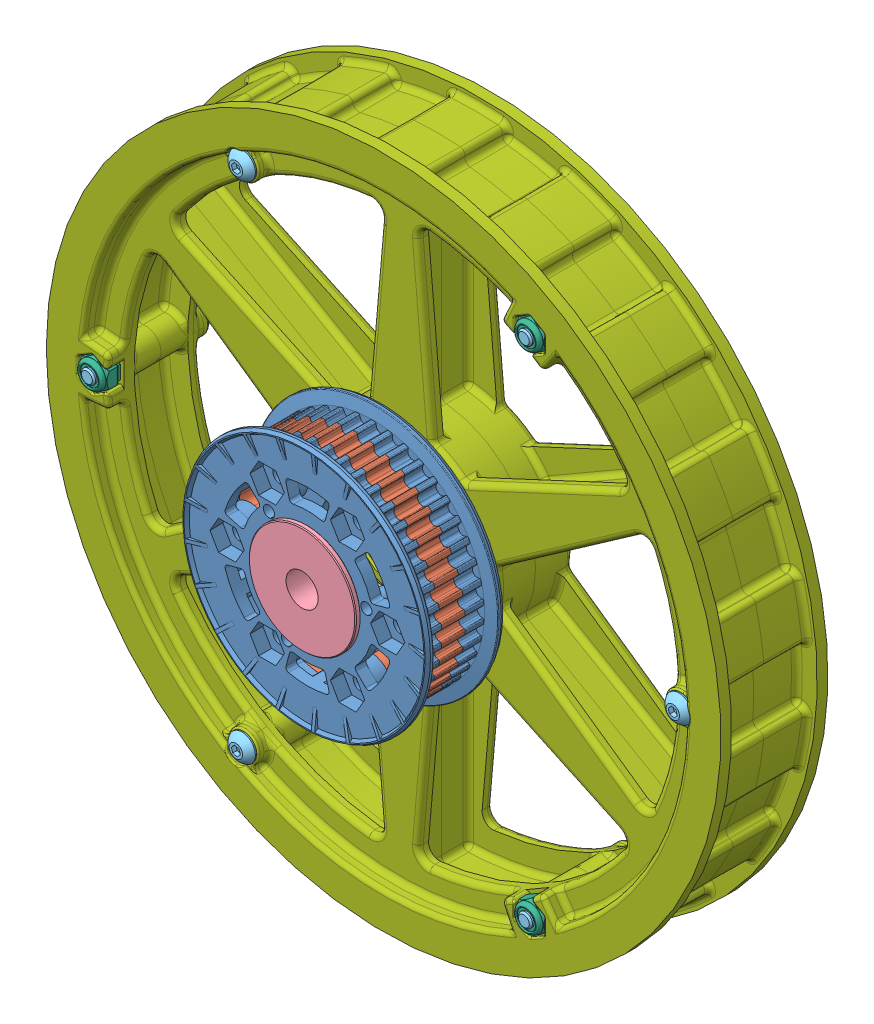
SolidWorks assembly Wheel Drive Free 2.1, configuration 8in Wheel. Lengths in mm.
Overall size (273.24 273.24 57.5).
51 component instances, 11 part files, 20 mates.
Components (placement in the parent):
- 217-2589 1in.20121203-1: 217-2589 1in.20121203 [Default] at origin size (158.75 158.75 36.2) (suppressed, hidden)
  - 217-2589-001 Rev3-1: 217-2589-001 Rev3 [Default] at origin size (149.22 149.22 19.81)
  - 217-2589-001 Rev3-2: 217-2589-001 Rev3 [Default] x (-1 0 0) z (0 0 -1) size (149.22 149.22 19.81)
  - SCREW-832-1250-1: SCREW-832-1250 [Default] at (60.96 0 -15.8623) x (0 0 1) z (-1 0 0) size (33.96 7.92 7.92)
  - NUT-832-NYLOCK-1: NUT-832-NYLOCK [Default] at (60.96 0 12.0688) x (0.866025 0.5 0) z (0.5 -0.866025 0) size (10.2 5.86 8.12)
  - BEAM-0750-1: BEAM-0750 [Default] at (11.9062 -20.6222 0.0635) x (0.866025 0.5 0) z (-0.5 0.866025 0) size (7.34 19.93 7.34)
  - BEAM-0750-2: BEAM-0750 [Default] at (-11.9062 -20.6222 0.0635) x (0.866025 -0.5 0) z (0.5 0.866025 0) size (7.34 19.93 7.34)
  - BEAM-0750-3: BEAM-0750 [Default] at (-23.8125 0 0.0635) x (0 -1 0) z (1 0 0) size (7.34 19.93 7.34)
  - BEAM-0750-4: BEAM-0750 [Default] at (-11.9062 20.6222 0.0635) x (-0.866025 -0.5 0) z (0.5 -0.866025 0) size (7.34 19.93 7.34)
  - BEAM-0750-5: BEAM-0750 [Default] at (11.9062 20.6222 0.0635) x (-0.866025 0.5 0) z (-0.5 -0.866025 0) size (7.34 19.93 7.34)
  - BEAM-0750-6: BEAM-0750 [Default] at (23.8125 0 0.0635) x (0 1 0) z (-1 0 0) size (7.34 19.93 7.34)
  - SCREW-832-1250-2: SCREW-832-1250 [Default] at (30.48 52.7929 15.8623) x (0 0 -1) z (0.923728 0.383049 0) size (33.96 7.92 7.92)
  - NUT-832-NYLOCK-2: NUT-832-NYLOCK [Default] at (30.48 52.7929 -12.0688) x (-0.866025 -0.5 0) z (0.5 -0.866025 0) size (10.2 5.86 8.12)
  - NUT-832-NYLOCK-3: NUT-832-NYLOCK [Default] at (30.48 -52.7929 -12.0688) x (0 1 0) z (-1 0 0) size (10.2 5.86 8.12)
  - NUT-832-NYLOCK-4: NUT-832-NYLOCK [Default] at (-60.96 0 -12.0688) x (0.866025 -0.5 0) z (0.5 0.866025 0) size (10.2 5.86 8.12)
  - SCREW-832-1250-3: SCREW-832-1250 [Default] at (-30.48 -52.7929 -15.8623) x (0 0 1) z (0.5 0.866025 0) size (33.96 7.92 7.92)
  - SCREW-832-1250-4: SCREW-832-1250 [Default] at (-30.48 52.7929 -15.8623) x (0 0 1) z (0.5 -0.866025 0) size (33.96 7.92 7.92)
  - NUT-832-NYLOCK-5: NUT-832-NYLOCK [Default] at (-30.48 -52.7929 12.0688) x (0 -1 0) z (-1 0 0) size (10.2 5.86 8.12)
  - NUT-832-NYLOCK-6: NUT-832-NYLOCK [Default] at (-30.48 52.7929 12.0688) x (-0.866025 0.5 0) z (0.5 0.866025 0) size (10.2 5.86 8.12)
  - SCREW-832-1250-5: SCREW-832-1250 [Default] at (30.48 -52.7929 15.8623) x (0 0 -1) z (-0.130134 -0.991496 0) size (33.96 7.92 7.92)
  - SCREW-832-1250-6: SCREW-832-1250 [Default] at (-60.96 0 15.8623) x (0 0 -1) z (-0.793594 0.608447 0) size (33.96 7.92 7.92)
  - 217-2860-001 Rev3-1: 217-2860-001 Rev3 [Default] at (0 0 -6.35) size (158.75 158.75 12.71)
  - 217-2860-001 Rev3-2: 217-2860-001 Rev3 [Default] at (0 0 6.35) size (158.75 158.75 12.71)
- 217-3199-STEP-1: 217-3199-STEP [Default] at (0 0 36.875) x (0 -1 0) z (0 0 1) size (73 73 23.01)
  - 217-3199-001 Rev4-1: 217-3199-001 Rev4 [Default] at origin size (73 73 11.51)
  - 217-3199-001 Rev4-2: 217-3199-001 Rev4 [Default] at (0 0 -17.825) x (-1 0 0) z (0 0 -1) size (73 73 11.51)
  - 217-3199-002 Rev3-1: 217-3199-002 Rev3 [Default] at (0 0 -5.5) x (-1 0 0) z (0 0 1) size (65.74 65.61 14)
- 217-3234-STEP-1: 217-3234-STEP [Default] at (0 0 14.2875) x (-0.866025 -0.5 0) z (0.5 -0.866025 0)
- 3_8 id 1-1_8 od Flanged Ball Bearing (am-0573)-1: 3_8 id 1-1_8 od Flanged Ball Bearing (am-0573) [Default] at (0 0 36.0749) x (0 0 1) z (-0.999645 0.02665 0)
- 3_8 id 1-1_8 od Flanged Ball Bearing (am-0573)-2: 3_8 id 1-1_8 od Flanged Ball Bearing (am-0573) [Default] at (0 0 -8.7249) x (0 0 -1) z (0.805779 0.592216 0)
- 217-2605 1in.20121203-1: 217-2605 1in.20121203 [Default] at origin size (273.24 273.24 34.92)
  - SBS1_SBS0832-1250SS-1: SBS1_SBS0832-1250SS [Default] at (-86.36 0 -16.4973) x (0 0 1) z (0.950435 -0.310923 0) size (34.41 8.02 7.99)
  - SBS1_SBS0832-1250SS-2: SBS1_SBS0832-1250SS [Default] at (-43.18 74.79 16.4973) x (0 0 -1) z (-0.955409 -0.295284 0) size (34.41 8.02 7.99)
  - NUT-832-NYLOCK-1: NUT-832-NYLOCK [Default] at (-86.36 0 12.0688) x (0.866025 0.5 0) z (0.5 -0.866025 0) size (10.2 5.86 8.12)
  - NUT-832-NYLOCK-2: NUT-832-NYLOCK [Default] at (-43.18 74.79 -12.0688) x (-0.866025 -0.5 0) z (0.5 -0.866025 0) size (10.2 5.86 8.12)
  - 217-2605-001 Rev1-1: 217-2605-001 Rev1 [Default] x (-0.5 0.866025 0) z (0 0 1) size (200.03 200.03 19.71)
  - 217-2605-001 Rev1-2: 217-2605-001 Rev1 [Default] x (-1 0 0) z (0 0 -1) size (200.03 200.03 19.71)
  - NUT-832-NYLOCK-3: NUT-832-NYLOCK [Default] at (86.36 0 -12.0688) x (0 1 0) z (-1 0 0) size (10.2 5.86 8.12)
  - NUT-832-NYLOCK-4: NUT-832-NYLOCK [Default] at (-43.18 -74.79 -12.0688) x (0.866025 -0.5 0) z (0.5 0.866025 0) size (10.2 5.86 8.12)
  - NUT-832-NYLOCK-5: NUT-832-NYLOCK [Default] at (43.18 74.79 12.0688) x (0 -1 0) z (-1 0 0) size (10.2 5.86 8.12)
  - NUT-832-NYLOCK-6: NUT-832-NYLOCK [Default] at (43.18 -74.79 12.0688) x (-0.866025 0.5 0) z (0.5 0.866025 0) size (10.2 5.86 8.12)
  - SBS1_SBS0832-1250SS-3: SBS1_SBS0832-1250SS [Default] at (43.18 74.79 -16.4973) x (0 0 1) z (-0.744485 -0.66764 0) size (34.41 8.02 7.99)
  - SBS1_SBS0832-1250SS-4: SBS1_SBS0832-1250SS [Default] at (43.18 -74.79 -16.4973) x (0 0 1) z (-0.20595 0.978562 0) size (34.41 8.02 7.99)
  - SBS1_SBS0832-1250SS-5: SBS1_SBS0832-1250SS [Default] at (86.36 0 16.4973) x (0 0 -1) z (0.221981 0.975051 0) size (34.41 8.02 7.99)
  - SBS1_SBS0832-1250SS-6: SBS1_SBS0832-1250SS [Default] at (-43.18 -74.79 16.4973) x (0 0 -1) z (0.733429 -0.679767 0) size (34.41 8.02 7.99)
  - BEAM-0750-1: BEAM-0750 [Default] at (-23.8125 0 0) x (0.866025 0.5 0) z (-0.5 0.866025 0) size (7.34 19.93 7.34)
  - BEAM-0750-2: BEAM-0750 [Default] at (-11.9062 20.6222 0) x (0.866025 -0.5 0) z (0.5 0.866025 0) size (7.34 19.93 7.34)
  - BEAM-0750-3: BEAM-0750 [Default] at (11.9062 20.6222 0) x (0 -1 0) z (1 0 0) size (7.34 19.93 7.34)
  - BEAM-0750-4: BEAM-0750 [Default] at (23.8125 0 0) x (-0.866025 -0.5 0) z (0.5 -0.866025 0) size (7.34 19.93 7.34)
  - BEAM-0750-5: BEAM-0750 [Default] at (11.9062 -20.6222 0) x (-0.866025 0.5 0) z (-0.5 -0.866025 0) size (7.34 19.93 7.34)
  - BEAM-0750-6: BEAM-0750 [Default] at (-11.9062 -20.6222 0) x (0 1 0) z (-1 0 0) size (7.34 19.93 7.34)
Mates (geometry in assembly coordinates):
- Coincident1: coincident aligned: plane of ? through (0 0 11.1125) normal (0 0 -1); plane of ? through (0 0 11.1125) normal (0 0 -1)
- Concentric1: concentric anti-aligned: cylinder of ? through (0 0 11.1125) axis (0 0 -1) radius 14.3; cylinder of 217-3199-STEP-1/217-3199-001 Rev4-2 through (0 0 17.4625) axis (0 0 1) radius 14.3
- Concentric2: concentric anti-aligned: cylinder of 217-2589 1in.20121203-1/BEAM-0750-2 through (-11.9062 -20.6222 9.5885) axis (0 0 -1) radius 2.0955; cylinder of 217-3199-STEP-1/217-3199-002 Rev3-1 through (-11.9062 -20.6222 29.7875) axis (0 0 1) radius 2.1526
- Concentric3: concentric aligned: cylinder of ? through (0 0 11.1125) axis (0 0 -1) radius 14.3; cylinder of ? through (0 0 17.4625) axis (0 0 -1) radius 14.3
- Concentric4: concentric anti-aligned: cylinder of ? through (-11.9062 -20.6222 14.2875) axis (0 0 1) radius 2.1526; cylinder of 217-2589 1in.20121203-1/217-2589-001 Rev3-1 through (-11.9062 -20.6222 -7.9375) axis (0 0 -1) radius 2.1526
- Coincident2: coincident anti-aligned: plane of 217-3199-STEP-1/217-3199-001 Rev4-2 through (0 0 17.4625) normal (0 0 -1); plane of 217-3234-STEP-1 through (0 0 17.4625) normal (0 0 1)
- Concentric5: concentric anti-aligned: cylinder of 217-3199-STEP-1/217-3199-001 Rev4-1 through (0 0 38.4625) axis (0 0 -1) radius 14.3; cylinder of 3_8 id 1-1_8 od Flanged Ball Bearing (am-0573)-1 through (0 0 40.0373) axis (0 0 1) radius 14.2875
- Coincident3: coincident anti-aligned: plane of 217-3199-STEP-1/217-3199-001 Rev4-1 through (0 0 38.4625) normal (0 0 1); plane of 3_8 id 1-1_8 od Flanged Ball Bearing (am-0573)-1 through (0.3808 14.2824 38.4625) normal (0 0 -1)
- Concentric6: concentric anti-aligned: cylinder of 217-2589 1in.20121203-1/217-2589-001 Rev3-1 through (0 0 -11.1125) axis (0 0 1) radius 14.3; cylinder of ? through (0 0 -12.6873) axis (0 0 -1) radius 14.2875
- Coincident4: coincident aligned: plane of 217-2589 1in.20121203-1/217-2589-001 Rev3-1 through (0 0 -11.1125) normal (0 0 1); plane of ? through (0 14.2875 -11.1125) normal (0 0 1)
- Coincident5: coincident aligned: plane of 217-2589 1in.20121203-1/217-2589-001 Rev3-1 through (0 0 0) normal (0 0 1); plane of assembly through (0 0 0) normal (0 0 1)
- Coincident6: coincident aligned: plane of 217-2589 1in.20121203-1/217-2589-001 Rev3-1 through (0 0 0) normal (0 1 0); plane of assembly through (0 0 0) normal (0 1 0)
- Coincident7: coincident aligned: plane of 217-2589 1in.20121203-1/217-2589-001 Rev3-1 through (0 0 0) normal (1 0 0); plane of assembly through (0 0 0) normal (1 0 0)
- Concentric7: concentric anti-aligned: cylinder of 3_8 id 1-1_8 od Flanged Ball Bearing (am-0573)-2 through (0 0 -12.6873) axis (0 0 -1) radius 14.2875; cylinder of 217-2605 1in.20121203-1/217-2605-001 Rev1-1 through (0 0 -11.1125) axis (0 0 1) radius 14.3
- Coincident8: coincident anti-aligned: plane of 3_8 id 1-1_8 od Flanged Ball Bearing (am-0573)-2 through (-8.4613 11.5126 -11.1125) normal (0 0 1); plane of 217-2605 1in.20121203-1/217-2605-001 Rev1-1 through (0 0 -11.1125) normal (0 0 -1)
- Concentric9: concentric aligned: cylinder of 217-3234-STEP-1 through (0 0 17.4625) axis (0 0 -1) radius 14.3; cylinder of ? through (0 0 11.1125) axis (0 0 -1) radius 14.3
- Concentric10: concentric aligned: cylinder of 217-3234-STEP-1 through (-11.9062 20.6222 14.2875) axis (0 0 1) radius 2.1526; cylinder of ? through (-11.9062 20.6222 7.9375) axis (0 0 1) radius 2.1526
- Coincident9: coincident anti-aligned: plane of 217-3234-STEP-1 through (0 0 11.1125) normal (0 0 -1); plane of ? through (0 0 11.1125) normal (0 0 1)
- Concentric11: concentric anti-aligned: cylinder of 217-3199-STEP-1/217-3199-001 Rev4-2 through (23.8125 0 20.6375) axis (0 0 -1) radius 2.1526; cylinder of 217-3234-STEP-1 through (23.8125 0 14.2875) axis (0 0 1) radius 2.1526
- Concentric12: concentric anti-aligned: cylinder of 217-3199-STEP-1/217-3199-001 Rev4-2 through (0 0 17.4625) axis (0 0 1) radius 14.3; cylinder of 217-3234-STEP-1 through (0 0 17.4625) axis (0 0 -1) radius 14.3
